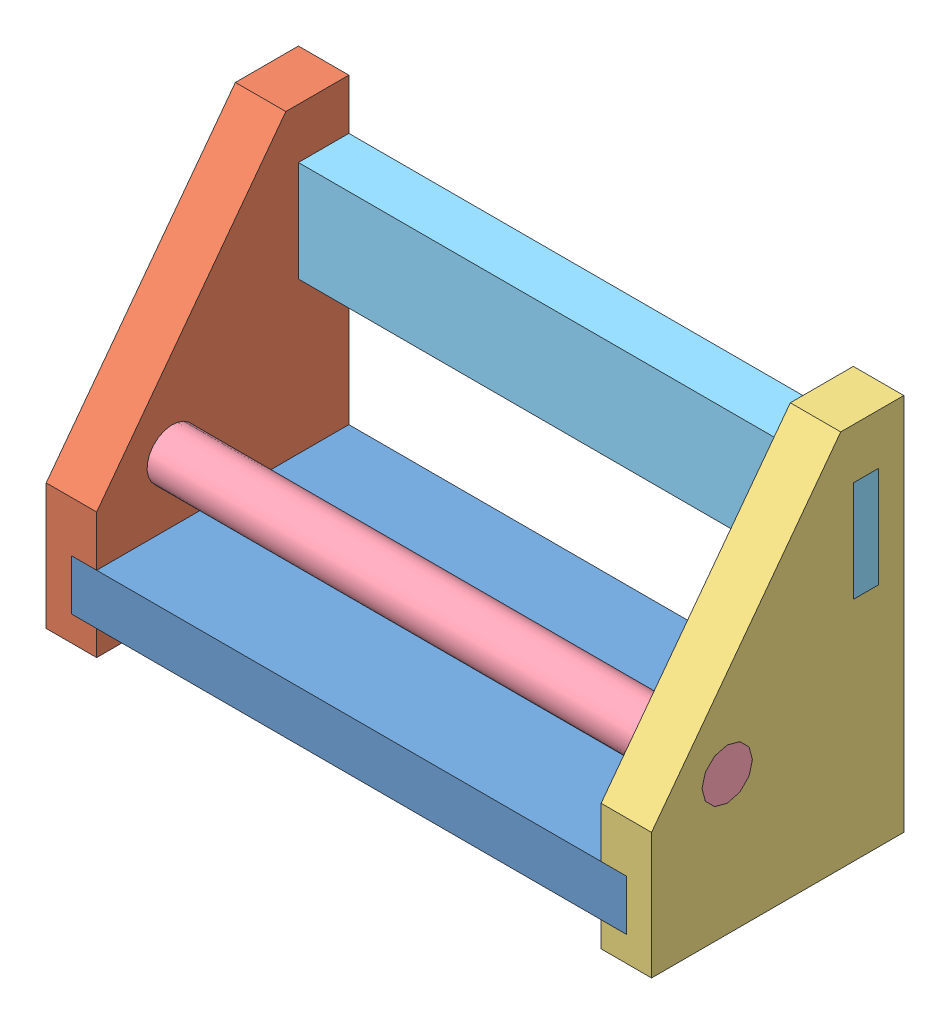
SolidWorks assembly SPICE RACK3, configuration Default. Lengths in mm.
Overall size (240 150 100).
5 component instances, 5 part files, 11 mates.
Components (placement in the parent):
- BOTTOM-2: BOTTOM [Default] at origin size (220 20 100)
- SIDE2-2: SIDE2 [Default] at (10 -10 -100) x (0 0 1) z (-1 0 0) size (100 150 20)
- SIDE-3: SIDE [Default] at (230 -10 -100) x (0 0 1) z (-1 0 0) size (100 150 20)
- DOWEL-1: DOWEL [Default] at (-10 45 -30) x (0 -0.184606 -0.982813) z (1 0 0) size (20 20 240)
- BACK-2: BACK [Default] at (-10 120 -80) x (1 0 0) z (0 0 -1) size (240 40 20)
Mates (geometry in assembly coordinates):
- Coincident4: coincident anti-aligned: plane of BOTTOM-2 through (0 20 0) normal (-1 0 0); plane of SIDE2-2 through (0 0 -100) normal (1 0 0)
- Coincident5: coincident anti-aligned: plane of BOTTOM-2 through (0 0 -100) normal (0 -1 0); plane of SIDE2-2 through (0 0 -100) normal (0 1 0)
- Coincident6: coincident aligned: line of BOTTOM-2 through (0 0 0) axis (1 0 0); line of SIDE2-2 through (0 0 0) axis (1 0 0)
- Coincident7: coincident anti-aligned: plane of BOTTOM-2 through (220 20 0) normal (1 0 0); plane of SIDE-3 through (220 0 0) normal (-1 0 0)
- Coincident8: coincident aligned: plane of BOTTOM-2 through (0 20 0) normal (0 0 1); plane of SIDE-3 through (210 40 0) normal (0 0 1)
- Coincident9: coincident anti-aligned: plane of SIDE-3 through (220 0 0) normal (0 1 0)
- Coincident10: coincident aligned: plane of SIDE-3 through (230 -10 -100) normal (1 0 0); plane of DOWEL-1 through (230 45 -30) normal (1 0 0)
- Coincident11: coincident anti-aligned: circle of ?; circle of ?
- Coincident12: coincident anti-aligned: plane of SIDE-3 through (210 120 -90) normal (0 0 1); plane of BACK-2 through (230 120 -90) normal (0 0 -1)
- Coincident13: coincident aligned: plane of BACK-2 through (230 120 -100) normal (1 0 0)
- Coincident14: coincident anti-aligned: line of SIDE-3 through (230 120 -80) axis (0 0 -1); line of BACK-2 through (230 120 -90) axis (0 0 1)
